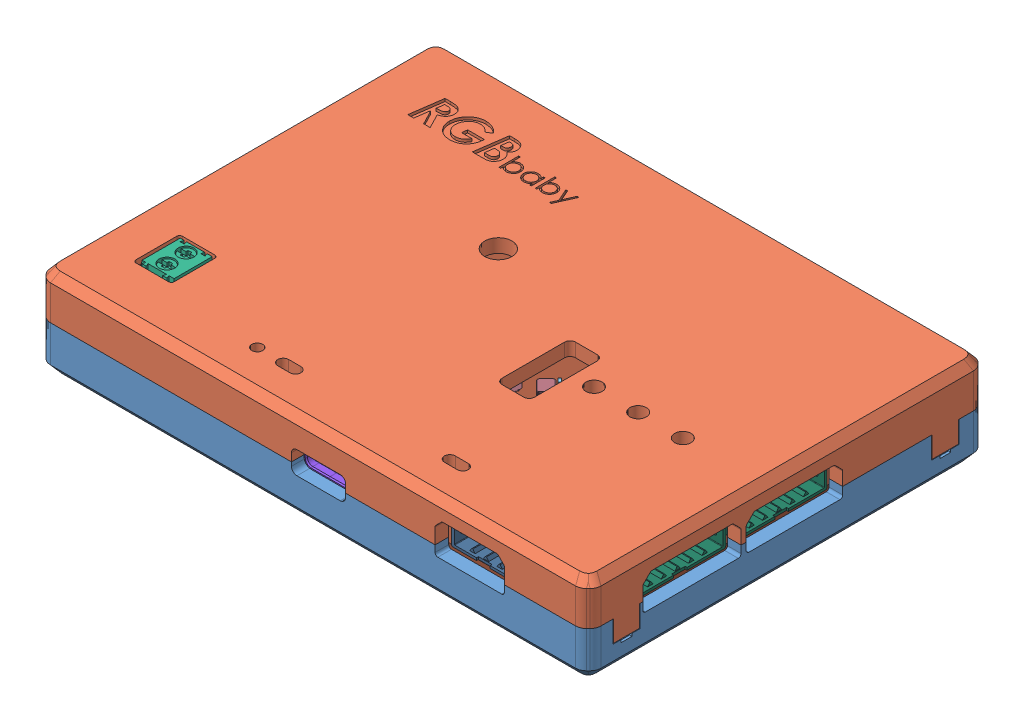
SolidWorks assembly LedDriverBoard_case, configuration Default. Lengths in mm.
Overall size (101 16.35 73).
222 component instances, 29 part files, 9 mates.
Components (placement in the parent):
- bottom-1: bottom [Default] at (41.875 48.3442 84.9116) size (101 8.5 73)
- top-1: top [Default] at (41.875 56.8442 84.9116) size (101 11.75 73)
- LedDriverBoard_V2.step-2: LedDriverBoard_V2.step [Default] at (41.875 53.8442 84.9116) x (1 0 0) z (0 1 0) size (95.69 68.17 13.7)
  - R_0603_1608Metric.step-1: R_0603_1608Metric.step [Default] at (-17.4387 -25.5512 1.65) x (0 -1 0) z (0 0 1) size (1.6 0.8 0.45)
    - SOLID.step-1: SOLID.step [Default] at origin size (1.6 0.8 0.45)
  - C_0603_1608Metric.step-1: C_0603_1608Metric.step [Default] at (31.25 11.3625 1.65) x (0 -1 0) z (0 0 1) size (1.6 0.8 0.8)
    - SOLID-0.step-1: SOLID-0.step [Default] at origin size (1.6 0.8 0.8)
  - C_0603_1608Metric.step-2: C_0603_1608Metric.step [Default] at (19.7 -1.25 1.65) size (1.6 0.8 0.8)
    - SOLID-0.step-1: SOLID-0.step [Default] at origin size (1.6 0.8 0.8)
  - R_0603_1608Metric.step-2: R_0603_1608Metric.step [Default] at (17.9613 -25.62 1.65) x (0 -1 0) z (0 0 1) size (1.6 0.8 0.45)
    - SOLID.step-1: SOLID.step [Default] at origin size (1.6 0.8 0.45)
  - C_0603_1608Metric.step-3: C_0603_1608Metric.step [Default] at (-15.6375 1.68 1.65) size (1.6 0.8 0.8)
    - SOLID-0.step-1: SOLID-0.step [Default] at origin size (1.6 0.8 0.8)
  - R_0603_1608Metric.step-3: R_0603_1608Metric.step [Default] at (-2.038 11.44 1.65) x (0 -1 0) z (0 0 1) size (1.6 0.8 0.45)
    - SOLID.step-1: SOLID.step [Default] at origin size (1.6 0.8 0.45)
  - R_0603_1608Metric.step-4: R_0603_1608Metric.step [Default] at (17 -4.65 1.65) x (0 1 0) z (0 0 1) size (1.6 0.8 0.45)
    - SOLID.step-1: SOLID.step [Default] at origin size (1.6 0.8 0.45)
  - C_0603_1608Metric.step-4: C_0603_1608Metric.step [Default] at (24.75 17 1.65) size (1.6 0.8 0.8)
    - SOLID-0.step-1: SOLID-0.step [Default] at origin size (1.6 0.8 0.8)
  - TE_1-84952-6_1x16-1MP_P1.0mm_Horizontal.step-1: TE_1-84952-6_1x16-1MP_P1.0mm_Horizontal.step [Default] at (-38.9 -3.45 1.65) x (0 -1 0) z (0 0 1) size (23.92 6.54 2.56)
    - SOLID-1.step-1: SOLID-1.step [Default] at origin size (23.92 6.54 2.56)
  - TLC59401RHBR.step-1: TLC59401RHBR.step [Default] at (31.75 17.5 1.65) x (-1 0 0) z (0 0 1) size (5 5 1)
    - COMPOUND.step-1: COMPOUND.step [Default] at origin size (5 5 1)
  - C_1206_3216Metric.step-1: C_1206_3216Metric.step [Default] at (10.9 -26.625 1.65) x (-1 0 0) z (0 0 1) size (3.2 1.6 1.6)
    - SOLID-2.step-1: SOLID-2.step [Default] at origin size (3.2 1.6 1.6)
  - USB_C_Receptacle_GCT_USB4105-xx-A_16P_TopMnt_Horizontal.step-1: USB_C_Receptacle_GCT_USB4105-xx-A_16P_TopMnt_Horizontal.step [Default] at (1.01 -31 1.65) size (8.94 7.78 4.26)
    - COMPOUND-3.step-1: COMPOUND-3.step [Default] at origin size (8.94 7.78 4.26)
  - C_1206_3216Metric.step-2: C_1206_3216Metric.step [Default] at (10.9625 -19.875 1.65) size (3.2 1.6 1.6)
    - SOLID-2.step-1: SOLID-2.step [Default] at origin size (3.2 1.6 1.6)
  - C_0603_1608Metric.step-5: C_0603_1608Metric.step [Default] at (-3.5 -15.4825 1.65) x (0 -1 0) z (0 0 1) size (1.6 0.8 0.8)
    - SOLID-0.step-1: SOLID-0.step [Default] at origin size (1.6 0.8 0.8)
  - TE_2-84952-0_1x20-1MP_P1.0mm_Horizontal.step-1: TE_2-84952-0_1x20-1MP_P1.0mm_Horizontal.step [Default] at (-0.25 26.47 1.65) x (-1 0 0) z (0 0 1) size (27.92 6.54 2.56)
    - SOLID-4.step-1: SOLID-4.step [Default] at origin size (27.92 6.54 2.56)
  - R_0603_1608Metric.step-5: R_0603_1608Metric.step [Default] at (-32.25 -5.95 1.65) x (-1 0 0) z (0 0 1) size (1.6 0.8 0.45)
    - SOLID.step-1: SOLID.step [Default] at origin size (1.6 0.8 0.45)
  - C_0603_1608Metric.step-6: C_0603_1608Metric.step [Default] at (-1 2.0175 1.65) x (0 1 0) z (0 0 1) size (1.6 0.8 0.8)
    - SOLID-0.step-1: SOLID-0.step [Default] at origin size (1.6 0.8 0.8)
  - LED_0805_2012Metric.step-1: LED_0805_2012Metric.step [Default] at (17.9613 -29.37 1.65) x (0 1 0) z (0 0 1) size (2 1.25 1.1)
    - SOLID-5.step-1: SOLID-5.step [Default] at origin size (2 1.25 1.1)
  - R_0603_1608Metric.step-6: R_0603_1608Metric.step [Default] at (-10.4 -25.5762 1.65) x (0 -1 0) z (0 0 1) size (1.6 0.8 0.45)
    - SOLID.step-1: SOLID.step [Default] at origin size (1.6 0.8 0.45)
  - R_0603_1608Metric.step-7: R_0603_1608Metric.step [Default] at (22.4 -4.65 1.65) x (0 1 0) z (0 0 1) size (1.6 0.8 0.45)
    - SOLID.step-1: SOLID.step [Default] at origin size (1.6 0.8 0.45)
  - R_0603_1608Metric.step-8: R_0603_1608Metric.step [Default] at (1.75 -15.4825 1.65) x (0 1 0) z (0 0 1) size (1.6 0.8 0.45)
    - SOLID.step-1: SOLID.step [Default] at origin size (1.6 0.8 0.45)
  - R_0603_1608Metric.step-9: R_0603_1608Metric.step [Default] at (20.35 -25.62 1.65) x (0 -1 0) z (0 0 1) size (1.6 0.8 0.45)
    - SOLID.step-1: SOLID.step [Default] at origin size (1.6 0.8 0.45)
  - R_0603_1608Metric.step-10: R_0603_1608Metric.step [Default] at (-15.6625 3.2675 1.65) size (1.6 0.8 0.45)
    - SOLID.step-1: SOLID.step [Default] at origin size (1.6 0.8 0.45)
  - Fuse_0805_2012Metric.step-1: Fuse_0805_2012Metric.step [Default] at (12.4 21.025 1.65) x (0 1 0) z (0 0 1) size (2 1.25 0.45)
    - SOLID-6.step-1: SOLID-6.step [Default] at origin size (2 1.25 0.45)
  - R_0603_1608Metric.step-11: R_0603_1608Metric.step [Default] at (-18.1 11.4625 1.65) x (0 -1 0) z (0 0 1) size (1.6 0.8 0.45)
    - SOLID.step-1: SOLID.step [Default] at origin size (1.6 0.8 0.45)
  - C_0603_1608Metric.step-7: C_0603_1608Metric.step [Default] at (0.5 2.0175 1.65) x (0 1 0) z (0 0 1) size (1.6 0.8 0.8)
    - SOLID-0.step-1: SOLID-0.step [Default] at origin size (1.6 0.8 0.8)
  - TLC59401RHBR.step-2: TLC59401RHBR.step [Default] at (-32.25 17.622 1.65) x (-1 0 0) z (0 0 1) size (5 5 1)
    - COMPOUND.step-1: COMPOUND.step [Default] at origin size (5 5 1)
  - TLC59401RHBR.step-3: TLC59401RHBR.step [Default] at (-0.264 17.47 1.65) x (-1 0 0) z (0 0 1) size (5 5 1)
    - COMPOUND.step-1: COMPOUND.step [Default] at origin size (5 5 1)
  - LED_0805_2012Metric.step-2: LED_0805_2012Metric.step [Default] at (-17.4387 -29.3012 1.65) x (0 1 0) z (0 0 1) size (2 1.25 1.1)
    - SOLID-5.step-1: SOLID-5.step [Default] at origin size (2 1.25 1.1)
  - PCA9670BS,118.step-1: PCA9670BS,118.step [Default] at (-42.25 17.525 1.65) x (0 -1 0) z (0 0 1) size (3.1 3.1 1)
    - COMPOUND-7.step-1: COMPOUND-7.step [Default] at origin size (3.1 3.1 1)
  - C_0603_1608Metric.step-8: C_0603_1608Metric.step [Default] at (4.75 -15.4825 1.65) x (0 -1 0) z (0 0 1) size (1.6 0.8 0.8)
    - SOLID-0.step-1: SOLID-0.step [Default] at origin size (1.6 0.8 0.8)
  - Crystal_SMD_3225-4Pin_3.2x2.5mm_HandSoldering.step-1: Crystal_SMD_3225-4Pin_3.2x2.5mm_HandSoldering.step [Default] at (6.5 -0.2325 1.65) x (-0.707107 0.707107 0) z (0 0 1) size (3.2 2.5 0.64)
    - SOLID-8.step-1: SOLID-8.step [Default] at origin size (3.2 2.5 0.64)
  - SS26SHE3_B_H.step-1: SS26SHE3_B_H.step [Default] at (-28.15 -15.25 1.65) size (5.11 2.67 2.29)
    - COMPOUND-9.step-1: COMPOUND-9.step [Default] at origin size (5.11 2.67 2.29)
  - C_0603_1608Metric.step-9: C_0603_1608Metric.step [Default] at (-27.2 -9.05 1.65) size (1.6 0.8 0.8)
    - SOLID-0.step-1: SOLID-0.step [Default] at origin size (1.6 0.8 0.8)
  - 1778667.step-1: 1778667.step [Default] at (48.1575 -6.97 1.65) x (0 1 0) z (0 0 1) size (16.72 7.5 7.12)
    - COMPOUND-10.step-1: COMPOUND-10.step [Default] at origin size (16.72 7.5 7.12)
  - Fuse_0805_2012Metric.step-2: Fuse_0805_2012Metric.step [Default] at (-19.7 20.85 1.65) x (0 1 0) z (0 0 1) size (2 1.25 0.45)
    - SOLID-6.step-1: SOLID-6.step [Default] at origin size (2 1.25 0.45)
  - SW_SPST_B3U-1000P.step-1: SW_SPST_B3U-1000P.step [Default] at (19.7 -4.65 1.65) x (0 1 0) z (0 0 1) size (4 2.51 1.59)
    - SOLID-11.step-1: SOLID-11.step [Default] at origin size (4 2.51 1.59)
  - LED_0805_2012Metric.step-3: LED_0805_2012Metric.step [Default] at (-12.65 -29.3263 1.65) x (0 1 0) z (0 0 1) size (2 1.25 1.1)
    - SOLID-5.step-1: SOLID-5.step [Default] at origin size (2 1.25 1.1)
  - R_0603_1608Metric.step-12: R_0603_1608Metric.step [Default] at (-32.25 -2.95 1.65) x (-1 0 0) z (0 0 1) size (1.6 0.8 0.45)
    - SOLID.step-1: SOLID.step [Default] at origin size (1.6 0.8 0.45)
  - PCA9670BS,118.step-2: PCA9670BS,118.step [Default] at (-10.27 17.52 1.65) x (0 -1 0) z (0 0 1) size (3.1 3.1 1)
    - COMPOUND-7.step-1: COMPOUND-7.step [Default] at origin size (3.1 3.1 1)
  - PCA9670BS,118.step-3: PCA9670BS,118.step [Default] at (20.75 17.25 1.65) x (0 -1 0) z (0 0 1) size (3.1 3.1 1)
    - COMPOUND-7.step-1: COMPOUND-7.step [Default] at origin size (3.1 3.1 1)
  - LED_0805_2012Metric.step-4: LED_0805_2012Metric.step [Default] at (-10.4 -29.3263 1.65) x (0 1 0) z (0 0 1) size (2 1.25 1.1)
    - SOLID-5.step-1: SOLID-5.step [Default] at origin size (2 1.25 1.1)
  - Fuseholder_Schurter_0031.7701.xx.step-1: Fuseholder_Schurter_0031.7701.xx.step [Default] at (-28.5 -21.75 1.65) x (-1 0 0) z (0 0 1) size (13.36 6.56 7.16)
    - COMPOUND-12.step-1: COMPOUND-12.step [Default] at origin size (13.36 6.56 7.16)
  - Fuse_0805_2012Metric.step-3: Fuse_0805_2012Metric.step [Default] at (40.3 20.85 1.65) x (0 1 0) z (0 0 1) size (2 1.25 0.45)
    - SOLID-6.step-1: SOLID-6.step [Default] at origin size (2 1.25 0.45)
  - C_1206_3216Metric.step-3: C_1206_3216Metric.step [Default] at (10.9 -29.375 1.65) x (-1 0 0) z (0 0 1) size (3.2 1.6 1.6)
    - SOLID-2.step-1: SOLID-2.step [Default] at origin size (3.2 1.6 1.6)
  - Fuse_0805_2012Metric.step-4: Fuse_0805_2012Metric.step [Default] at (-32.25 -7.75 1.65) size (2 1.25 0.45)
    - SOLID-6.step-1: SOLID-6.step [Default] at origin size (2 1.25 0.45)
  - C_0603_1608Metric.step-10: C_0603_1608Metric.step [Default] at (-15.5 8.5 1.65) x (0 1 0) z (0 0 1) size (1.6 0.8 0.8)
    - SOLID-0.step-1: SOLID-0.step [Default] at origin size (1.6 0.8 0.8)
  - SN74AHCT125DR.step-1: SN74AHCT125DR.step [Default] at (-25.3 -3.45 1.65) x (-1 0 0) z (0 0 1) size (6.03 8.65 1.75)
    - COMPOUND-13.step-1: COMPOUND-13.step [Default] at origin size (6.03 8.65 1.75)
  - C_0603_1608Metric.step-11: C_0603_1608Metric.step [Default] at (27.8 -1.25 1.65) size (1.6 0.8 0.8)
    - SOLID-0.step-1: SOLID-0.step [Default] at origin size (1.6 0.8 0.8)
  - L_0805_2012Metric.step-1: L_0805_2012Metric.step [Default] at (-3.5 -22.65 1.65) x (0 1 0) z (0 0 1) size (2 1.25 1.25)
    - SOLID-14.step-1: SOLID-14.step [Default] at origin size (2 1.25 1.25)
  - C_0603_1608Metric.step-12: C_0603_1608Metric.step [Default] at (2 2.0425 1.65) x (0 1 0) z (0 0 1) size (1.6 0.8 0.8)
    - SOLID-0.step-1: SOLID-0.step [Default] at origin size (1.6 0.8 0.8)
  - R_0603_1608Metric.step-13: R_0603_1608Metric.step [Default] at (25.1 -4.55 1.65) x (0 1 0) z (0 0 1) size (1.6 0.8 0.45)
    - SOLID.step-1: SOLID.step [Default] at origin size (1.6 0.8 0.45)
  - C_0603_1608Metric.step-13: C_0603_1608Metric.step [Default] at (44 16.25 1.65) size (1.6 0.8 0.8)
    - SOLID-0.step-1: SOLID-0.step [Default] at origin size (1.6 0.8 0.8)
  - R_0603_1608Metric.step-14: R_0603_1608Metric.step [Default] at (21.5 11.4125 1.65) x (0 1 0) z (0 0 1) size (1.6 0.8 0.45)
    - SOLID.step-1: SOLID.step [Default] at origin size (1.6 0.8 0.45)
  - SW_SPST_B3U-1000P.step-2: SW_SPST_B3U-1000P.step [Default] at (27.8 -4.65 1.65) x (0 1 0) z (0 0 1) size (4 2.51 1.59)
    - SOLID-11.step-1: SOLID-11.step [Default] at origin size (4 2.51 1.59)
  - R_0603_1608Metric.step-15: R_0603_1608Metric.step [Default] at (37.75 -22.75 1.65) x (-1 0 0) z (0 0 1) size (1.6 0.8 0.45)
    - SOLID.step-1: SOLID.step [Default] at origin size (1.6 0.8 0.45)
  - SOT-23-5.step-1: SOT-23-5.step [Default] at (11.0125 -23.075 1.65) size (2.8 2.9 1.55)
    - SOLID-15.step-1: SOLID-15.step [Default] at origin size (2.8 2.9 1.55)
  - R_0603_1608Metric.step-16: R_0603_1608Metric.step [Default] at (-43.2 11.55 1.65) x (0 -1 0) z (0 0 1) size (1.6 0.8 0.45)
    - SOLID.step-1: SOLID.step [Default] at origin size (1.6 0.8 0.45)
  - SW_SPST_B3U-1000P.step-3: SW_SPST_B3U-1000P.step [Default] at (10 -13.55 1.65) x (0 -1 0) z (0 0 1) size (4 2.51 1.59)
    - SOLID-11.step-1: SOLID-11.step [Default] at origin size (4 2.51 1.59)
  - C_0603_1608Metric.step-14: C_0603_1608Metric.step [Default] at (9 -5.9825 1.65) size (1.6 0.8 0.8)
    - SOLID-0.step-1: SOLID-0.step [Default] at origin size (1.6 0.8 0.8)
  - R_0603_1608Metric.step-17: R_0603_1608Metric.step [Default] at (-34 11.5345 1.65) x (0 -1 0) z (0 0 1) size (1.6 0.8 0.45)
    - SOLID.step-1: SOLID.step [Default] at origin size (1.6 0.8 0.45)
  - C_0603_1608Metric.step-15: C_0603_1608Metric.step [Default] at (35.9 -1.25 1.65) size (1.6 0.8 0.8)
    - SOLID-0.step-1: SOLID-0.step [Default] at origin size (1.6 0.8 0.8)
  - R_0603_1608Metric.step-18: R_0603_1608Metric.step [Default] at (0.25 -15.4825 1.65) x (0 1 0) z (0 0 1) size (1.6 0.8 0.45)
    - SOLID.step-1: SOLID.step [Default] at origin size (1.6 0.8 0.45)
  - SOT-143.step-1: SOT-143.step [Default] at (1.01 -22.55 1.65) size (2.8 2.9 1.2)
    - SOLID-16.step-1: SOLID-16.step [Default] at origin size (2.8 2.9 1.2)
  - R_0603_1608Metric.step-19: R_0603_1608Metric.step [Default] at (30.6 -4.55 1.65) x (0 1 0) z (0 0 1) size (1.6 0.8 0.45)
    - SOLID.step-1: SOLID.step [Default] at origin size (1.6 0.8 0.45)
  - TE_2-84952-0_1x20-1MP_P1.0mm_Horizontal.step-2: TE_2-84952-0_1x20-1MP_P1.0mm_Horizontal.step [Default] at (-32.25 26.45 1.65) x (-1 0 0) z (0 0 1) size (27.92 6.54 2.56)
    - SOLID-4.step-1: SOLID-4.step [Default] at origin size (27.92 6.54 2.56)
  - C_0603_1608Metric.step-16: C_0603_1608Metric.step [Default] at (-0.514 11.44 1.65) x (0 -1 0) z (0 0 1) size (1.6 0.8 0.8)
    - SOLID-0.step-1: SOLID-0.step [Default] at origin size (1.6 0.8 0.8)
  - Fuse_0805_2012Metric.step-5: Fuse_0805_2012Metric.step [Default] at (-32.225 -11.05 1.65) size (2 1.25 0.45)
    - SOLID-6.step-1: SOLID-6.step [Default] at origin size (2 1.25 0.45)
  - R_0603_1608Metric.step-20: R_0603_1608Metric.step [Default] at (7.4 -12.75 1.65) x (0 -1 0) z (0 0 1) size (1.6 0.8 0.45)
    - SOLID.step-1: SOLID.step [Default] at origin size (1.6 0.8 0.45)
  - Fuse_0805_2012Metric.step-6: Fuse_0805_2012Metric.step [Default] at (9 21.025 1.65) x (0 1 0) z (0 0 1) size (2 1.25 0.45)
    - SOLID-6.step-1: SOLID-6.step [Default] at origin size (2 1.25 0.45)
  - QFN-64-1EP_9x9mm_P0.5mm_EP4.7x4.7mm.step-1: QFN-64-1EP_9x9mm_P0.5mm_EP4.7x4.7mm.step [Default] at (-0.25 -6.82 1.65) x (0 -1 0) z (0 0 1) size (9 9 1.1)
    - SOLID-17.step-1: SOLID-17.step [Default] at origin size (9 9 1.1)
  - R_0603_1608Metric.step-21: R_0603_1608Metric.step [Default] at (30 -23.5875 1.65) x (0 -1 0) z (0 0 1) size (1.6 0.8 0.45)
    - SOLID.step-1: SOLID.step [Default] at origin size (1.6 0.8 0.45)
  - R_0603_1608Metric.step-22: R_0603_1608Metric.step [Default] at (37.75 -20.25 1.65) size (1.6 0.8 0.45)
    - SOLID.step-1: SOLID.step [Default] at origin size (1.6 0.8 0.45)
  - C_0603_1608Metric.step-17: C_0603_1608Metric.step [Default] at (-9 -5.2325 1.65) x (-1 0 0) z (0 0 1) size (1.6 0.8 0.8)
    - SOLID-0.step-1: SOLID-0.step [Default] at origin size (1.6 0.8 0.8)
  - R_0603_1608Metric.step-23: R_0603_1608Metric.step [Default] at (3.6 -22.55 1.65) x (0 1 0) z (0 0 1) size (1.6 0.8 0.45)
    - SOLID.step-1: SOLID.step [Default] at origin size (1.6 0.8 0.45)
  - TE_2-84952-0_1x20-1MP_P1.0mm_Horizontal.step-3: TE_2-84952-0_1x20-1MP_P1.0mm_Horizontal.step [Default] at (31.75 26.45 1.65) x (-1 0 0) z (0 0 1) size (27.92 6.54 2.56)
    - SOLID-4.step-1: SOLID-4.step [Default] at origin size (27.92 6.54 2.56)
  - C_0402_1005Metric.step-1: C_0402_1005Metric.step [Default] at (6.8487 1.9188 1.65) x (-0.707107 0.707107 0) z (0 0 1) size (1 0.5 0.5)
    - SOLID-18.step-1: SOLID-18.step [Default] at origin size (1 0.5 0.5)
  - R_0603_1608Metric.step-24: R_0603_1608Metric.step [Default] at (-12.65 -25.5762 1.65) x (0 -1 0) z (0 0 1) size (1.6 0.8 0.45)
    - SOLID.step-1: SOLID.step [Default] at origin size (1.6 0.8 0.45)
  - SW_SPST_B3U-1000P.step-4: SW_SPST_B3U-1000P.step [Default] at (36 -4.65 1.65) x (0 1 0) z (0 0 1) size (4 2.51 1.59)
    - SOLID-11.step-1: SOLID-11.step [Default] at origin size (4 2.51 1.59)
  - TerminalBlock_Phoenix_PT-1,5-2-3.5-H_1x02_P3.50mm_Horizontal.step-1: TerminalBlock_Phoenix_PT-1,5-2-3.5-H_1x02_P3.50mm_Horizontal.step [Default] at (-39.05 -20.75 1.65) x (0 -1 0) z (0 0 1) size (7.57 7.55 13.7)
    - SOLID-19.step-1: SOLID-19.step [Default] at origin size (7.57 7.55 13.7)
  - C_0805_2012Metric.step-1: C_0805_2012Metric.step [Default] at (-5.7 -22.65 1.65) x (0 -1 0) z (0 0 1) size (2 1.25 1.25)
    - SOLID-20.step-1: SOLID-20.step [Default] at origin size (2 1.25 1.25)
  - C_0603_1608Metric.step-18: C_0603_1608Metric.step [Default] at (-6 17.25 1.65) size (1.6 0.8 0.8)
    - SOLID-0.step-1: SOLID-0.step [Default] at origin size (1.6 0.8 0.8)
  - LED_0805_2012Metric.step-5: LED_0805_2012Metric.step [Default] at (20.35 -29.37 1.65) x (0 1 0) z (0 0 1) size (2 1.25 1.1)
    - SOLID-5.step-1: SOLID-5.step [Default] at origin size (2 1.25 1.1)
  - Fuse_0805_2012Metric.step-7: Fuse_0805_2012Metric.step [Default] at (43.7 20.875 1.65) x (0 1 0) z (0 0 1) size (2 1.25 0.45)
    - SOLID-6.step-1: SOLID-6.step [Default] at origin size (2 1.25 0.45)
  - C_0603_1608Metric.step-19: C_0603_1608Metric.step [Default] at (9 -7.4825 1.65) x (-1 0 0) z (0 0 1) size (1.6 0.8 0.8)
    - SOLID-0.step-1: SOLID-0.step [Default] at origin size (1.6 0.8 0.8)
  - R_0603_1608Metric.step-25: R_0603_1608Metric.step [Default] at (-32.25 3.05 1.65) x (-1 0 0) z (0 0 1) size (1.6 0.8 0.45)
    - SOLID.step-1: SOLID.step [Default] at origin size (1.6 0.8 0.45)
  - C_0603_1608Metric.step-20: C_0603_1608Metric.step [Default] at (-5 -15.4825 1.65) x (0 -1 0) z (0 0 1) size (1.6 0.8 0.8)
    - SOLID-0.step-1: SOLID-0.step [Default] at origin size (1.6 0.8 0.8)
  - L_0805_2012Metric.step-2: L_0805_2012Metric.step [Default] at (-2.75 2.0175 1.65) x (0 -1 0) z (0 0 1) size (2 1.25 1.25)
    - SOLID-14.step-1: SOLID-14.step [Default] at origin size (2 1.25 1.25)
  - C_0603_1608Metric.step-21: C_0603_1608Metric.step [Default] at (9 -4.4825 1.65) size (1.6 0.8 0.8)
    - SOLID-0.step-1: SOLID-0.step [Default] at origin size (1.6 0.8 0.8)
  - R_0603_1608Metric.step-26: R_0603_1608Metric.step [Default] at (23 11.4125 1.65) x (0 -1 0) z (0 0 1) size (1.6 0.8 0.45)
    - SOLID.step-1: SOLID.step [Default] at origin size (1.6 0.8 0.45)
  - R_0603_1608Metric.step-27: R_0603_1608Metric.step [Default] at (29.726 11.3625 1.65) x (0 -1 0) z (0 0 1) size (1.6 0.8 0.45)
    - SOLID.step-1: SOLID.step [Default] at origin size (1.6 0.8 0.45)
  - R_0603_1608Metric.step-28: R_0603_1608Metric.step [Default] at (7.65 -23.125 1.65) x (0 -1 0) z (0 0 1) size (1.6 0.8 0.45)
    - SOLID.step-1: SOLID.step [Default] at origin size (1.6 0.8 0.45)
  - Fuse_0805_2012Metric.step-8: Fuse_0805_2012Metric.step [Default] at (-23.2 20.85 1.65) x (0 1 0) z (0 0 1) size (2 1.25 0.45)
    - SOLID-6.step-1: SOLID-6.step [Default] at origin size (2 1.25 0.45)
  - C_0805_2012Metric.step-2: C_0805_2012Metric.step [Default] at (-5.6 -27.55 1.65) x (0 1 0) z (0 0 1) size (2 1.25 1.25)
    - SOLID-20.step-1: SOLID-20.step [Default] at origin size (2 1.25 1.25)
  - IS25LP032D-JLLE.step-1: IS25LP032D-JLLE.step [Default] at (-9.6 1.4225 1.65) size (6.1 5 0.75)
    - COMPOUND-21.step-1: COMPOUND-21.step [Default] at origin size (6.1 5 0.75)
  - LED_WS2812B_PLCC4_5.0x5.0mm_P3.2mm.step-1: LED_WS2812B_PLCC4_5.0x5.0mm_P3.2mm.step [Default] at (-11 8.5 1.65) size (5.4 5 1.6)
    - SOLID-22.step-1: SOLID-22.step [Default] at origin size (5.4 5 1.6)
  - 1778667.step-2: 1778667.step [Default] at (48.195 -25.6075 1.65) x (0 1 0) z (0 0 1) size (16.72 7.5 7.12)
    - COMPOUND-10.step-1: COMPOUND-10.step [Default] at origin size (16.72 7.5 7.12)
  - R_0603_1608Metric.step-29: R_0603_1608Metric.step [Default] at (33.3 -4.55 1.65) x (0 1 0) z (0 0 1) size (1.6 0.8 0.45)
    - SOLID.step-1: SOLID.step [Default] at origin size (1.6 0.8 0.45)
  - R_0603_1608Metric.step-30: R_0603_1608Metric.step [Default] at (-1.5 -22.55 1.65) x (0 1 0) z (0 0 1) size (1.6 0.8 0.45)
    - SOLID.step-1: SOLID.step [Default] at origin size (1.6 0.8 0.45)
  - R_0603_1608Metric.step-31: R_0603_1608Metric.step [Default] at (-32.25 0.05 1.65) x (-1 0 0) z (0 0 1) size (1.6 0.8 0.45)
    - SOLID.step-1: SOLID.step [Default] at origin size (1.6 0.8 0.45)
  - R_0603_1608Metric.step-32: R_0603_1608Metric.step [Default] at (38.7 -4.55 1.65) x (0 1 0) z (0 0 1) size (1.6 0.8 0.45)
    - SOLID.step-1: SOLID.step [Default] at origin size (1.6 0.8 0.45)
  - C_0603_1608Metric.step-22: C_0603_1608Metric.step [Default] at (-32.5 11.5095 1.65) x (0 -1 0) z (0 0 1) size (1.6 0.8 0.8)
    - SOLID-0.step-1: SOLID-0.step [Default] at origin size (1.6 0.8 0.8)
  - C_0402_1005Metric.step-2: C_0402_1005Metric.step [Default] at (8.6513 0.1162 1.65) x (0.707107 -0.707107 0) z (0 0 1) size (1 0.5 0.5)
    - SOLID-18.step-1: SOLID-18.step [Default] at origin size (1 0.5 0.5)
  - C_0603_1608Metric.step-23: C_0603_1608Metric.step [Default] at (44 18.01 1.65) size (1.6 0.8 0.8)
    - SOLID-0.step-1: SOLID-0.step [Default] at origin size (1.6 0.8 0.8)
  - 1778641.step-1: 1778641.step [Default] at (22.96 -33.999 1.79) size (11.72 7.5 7.12)
    - COMPOUND-23.step-1: COMPOUND-23.step [Default] at origin size (11.72 7.5 7.12)
  - R_0603_1608Metric.step-33: R_0603_1608Metric.step [Default] at (32.5 -23.5875 1.65) x (0 1 0) z (0 0 1) size (1.6 0.8 0.45)
    - SOLID.step-1: SOLID.step [Default] at origin size (1.6 0.8 0.45)
  - R_0603_1608Metric.step-34: R_0603_1608Metric.step [Default] at (-5.6 -31.3375 1.65) x (0 -1 0) z (0 0 1) size (1.6 0.8 0.45)
    - SOLID.step-1: SOLID.step [Default] at origin size (1.6 0.8 0.45)
  - R_0603_1608Metric.step-35: R_0603_1608Metric.step [Default] at (17.8 11.3625 1.65) x (0 -1 0) z (0 0 1) size (1.6 0.8 0.45)
    - SOLID.step-1: SOLID.step [Default] at origin size (1.6 0.8 0.45)
  - C_0603_1608Metric.step-24: C_0603_1608Metric.step [Default] at (-38.25 17.75 1.65) size (1.6 0.8 0.8)
    - SOLID-0.step-1: SOLID-0.step [Default] at origin size (1.6 0.8 0.8)
  - LedDriverBoard_V2 PCB.step-1: LedDriverBoard_V2 PCB.step [Default] at origin size (95 67 1.6)
Mates (geometry in assembly coordinates):
- Distance1: distance = 3 mm anti-aligned: plane of LedDriverBoard_V2.step-1/LedDriverBoard_V2 PCB.step-1 through (41.875 53.8442 84.9116) normal (0 -1 0); plane of bottom-1 through (41.875 50.8442 84.9116) normal (0 1 0)
- Width1: width anti-aligned: plane of LedDriverBoard_V2.step-1/LedDriverBoard_V2 PCB.step-1 through (-3.625 53.8442 51.4116) normal (0 0 -1); plane of LedDriverBoard_V2.step-1/LedDriverBoard_V2 PCB.step-1 through (87.375 53.8442 118.4116) normal (0 0 1); plane of bottom-1 through (-8.625 56.8442 50.9116) normal (0 0 1); plane of bottom-1 through (-8.625 56.8442 118.9116) normal (0 0 -1)
- Width2: width aligned: plane of LedDriverBoard_V2.step-1/LedDriverBoard_V2 PCB.step-1 through (89.375 53.8442 53.4116) normal (1 0 0); plane of LedDriverBoard_V2.step-1/LedDriverBoard_V2 PCB.step-1 through (-5.625 53.8442 116.4116) normal (-1 0 0); plane of bottom-1 through (-6.125 56.8442 121.4116) normal (1 0 0); plane of bottom-1 through (89.875 56.8442 121.4116) normal (-1 0 0)
- Width3: width anti-aligned: plane of top-1 through (-8.625 64.6942 121.4116) normal (0 0 1); plane of bottom-1 through (-8.625 64.6942 48.4116) normal (0 0 -1); plane of top-1 through (-8.625 56.8442 48.4116) normal (0 0 -1); plane of bottom-1 through (-8.625 56.8442 121.4116) normal (0 0 1)
- Width4: width anti-aligned: plane of top-1 through (92.375 64.6942 121.4116) normal (1 0 0); plane of bottom-1 through (-8.625 64.6942 121.4116) normal (-1 0 0); plane of top-1 through (-8.625 56.8442 121.4116) normal (-1 0 0); plane of bottom-1 through (92.375 56.8442 121.4116) normal (1 0 0)
- Coincident1: coincident anti-aligned: plane of bottom-1 through (41.875 56.8442 84.9116) normal (0 1 0); plane of top-1 through (41.875 56.8442 84.9116) normal (0 -1 0)
- Concentric1: concentric aligned: cylinder of bottom-1 through (17.625 46.8844 79.9116) axis (0 1 0) radius 1.4; cylinder of LedDriverBoard_V2.step-2/LedDriverBoard_V2 PCB.step-1 through (17.625 53.8342 79.9116) axis (0 1 0) radius 1.6
- Width5: width aligned: plane of LedDriverBoard_V2.step-2/LedDriverBoard_V2 PCB.step-1 through (89.375 53.8442 53.4116) normal (1 0 0); plane of bottom-1 through (-5.625 53.8442 116.4116) normal (-1 0 0); plane of LedDriverBoard_V2.step-2/LedDriverBoard_V2 PCB.step-1 through (-6.125 56.8442 121.4116) normal (1 0 0); plane of bottom-1 through (89.875 56.8442 121.4116) normal (-1 0 0)
- Width6: width aligned: plane of LedDriverBoard_V2.step-2/LedDriverBoard_V2 PCB.step-1 through (87.375 53.8442 118.4116) normal (0 0 1); plane of bottom-1 through (-3.625 53.8442 51.4116) normal (0 0 -1); plane of LedDriverBoard_V2.step-2/LedDriverBoard_V2 PCB.step-1 through (-8.625 56.8442 50.9116) normal (0 0 1); plane of bottom-1 through (-8.625 56.8442 118.9116) normal (0 0 -1)
